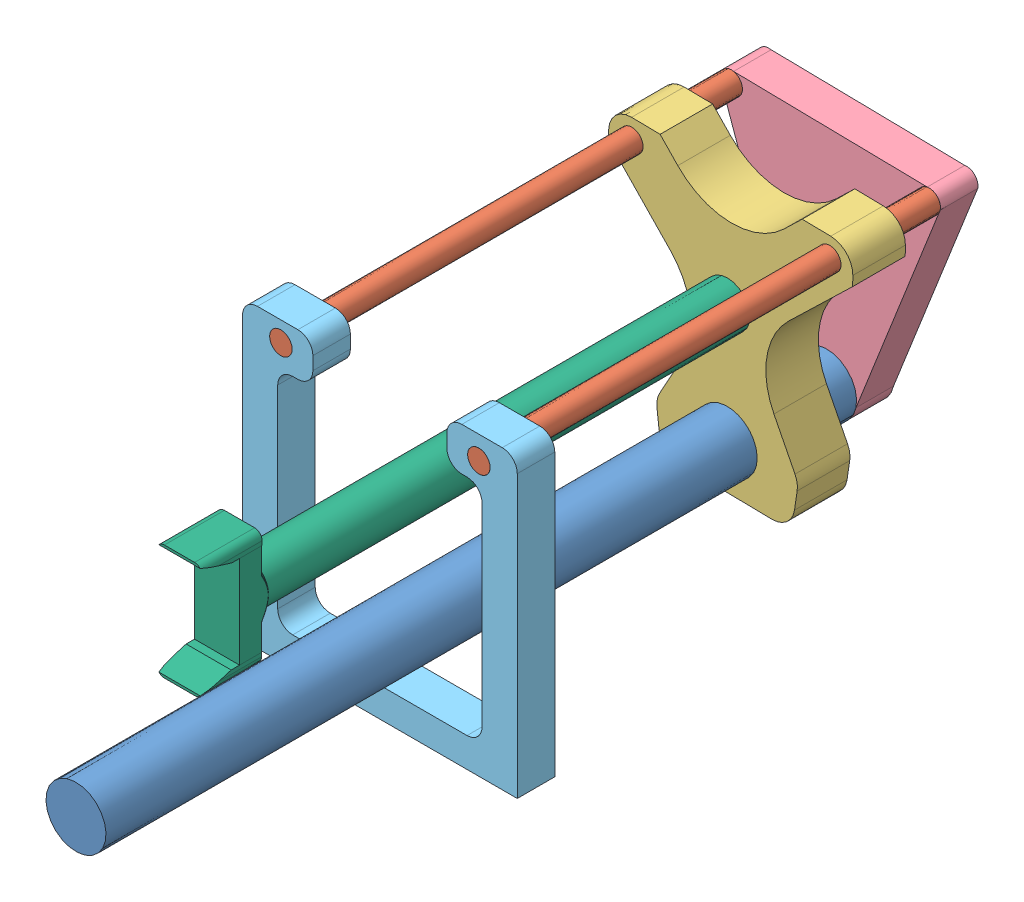
SolidWorks assembly Assem121, configuration Default. Lengths in mm.
Overall size (39.11 46.62 105).
8 component instances, 7 part files, 12 mates.
Components (placement in the parent):
- Partscrew-1: Partscrew [Default] at (36.3592 53.5498 26.3425) x (-0.97731 0.211815 0) z (0 0 1) size (8 8 100)
- Partrod-1: Partrod [Default] at (23.6562 81.9048 26.3425) size (3 3 60)
- Partrod-2: Partrod [Default] at (50.031 81.4507 86.3425) x (-0.449894 0.893082 0) z (0 0 -1) size (3 3 60)
- Partbase-1: Partbase [Default] at (36.624 68.9236 39.587) x (0 0 -1) z (0.999852 -0.017217 0) size (7 36.7 32.53)
- Part1^Assem121-1: Part1^Assem121 [Default] at (36.3592 53.5498 26.3425) x (0.97731 -0.211815 0) z (0 0 -1) size (28.87 35.66 5) (virtual)
- Part3^Assem121-1: Part3^Assem121 [Default] at origin (virtual)
- Part5^Assem121-1: Part5^Assem121 [Default] at (23.6562 81.9048 81.3425) size (36.61 46.62 5) (virtual)
- Partrod33-1: Partrod33 [Default] at (36.3928 69.376 39.587) size (9.64 17.18 73)
Mates (geometry in assembly coordinates):
- Coincident6: coincident aligned: plane of Partscrew-1 through (36.3592 53.5498 26.3425) normal (0 0 -1); plane of Partrod-2 through (50.031 81.4507 26.3425) normal (0 0 -1)
- Coincident7: coincident aligned: plane of Partscrew-1 through (36.3592 53.5498 26.3425) normal (0 0 -1); plane of Partrod-1 through (23.6562 81.9048 26.3425) normal (0 0 -1)
- Concentric2: concentric anti-aligned: circle of Partscrew-1; circle of Partbase-1
- Concentric3: concentric anti-aligned: circle of Partrod-1; circle of Partbase-1
- Concentric4: concentric aligned: circle of Partrod-2; circle of Partbase-1
- Coincident12: coincident aligned: plane of Partscrew-1 through (36.3592 53.5498 26.3425) normal (0 0 -1); plane of Partrod-2 through (50.031 81.4507 26.3425) normal (0 0 -1)
- InPlace1: in place: plane of Partscrew-1 through (36.3592 53.5498 26.3425) normal (0 0 -1); plane of ? through (0 0 26.3425) normal (0 0 -1); moOrthogonalPlaneRef_w of Partscrew-1 through (36.3592 53.5498 26.3425) normal (0 0 -1); plane of ? through (0 0 26.3425) normal (0 1 0); plane of Partscrew-1 through (36.3592 53.5498 26.3425) normal (0 0 -1); plane of ? through (0 0 26.3425) normal (-1 0 0); plane of Partscrew-1 through (36.3592 53.5498 26.3425) normal (0 0 -1); unknown of Part1^Assem121-1
- Coincident13: coincident aligned: plane of Partscrew-1; plane of Part1^Assem121-1
- Coincident14: coincident aligned: moOrthogonalPlaneRef_w of Partscrew-1 through (36.3592 53.5498 26.3425) normal (-0.211815 -0.97731 0); plane of Part1^Assem121-1 through (36.3592 53.5498 26.3425) normal (-0.211815 -0.97731 0)
- Coincident15: coincident anti-aligned: moOrthogonalPlaneRef_w of Partscrew-1 through (36.3592 53.5498 26.3425) normal (-0.97731 0.211815 0); plane of Part1^Assem121-1 through (36.3592 53.5498 26.3425) normal (0.97731 -0.211815 0)
- Coincident21: coincident aligned: plane of Partrod-1 through (23.6562 81.9048 86.3425) normal (0 0 1); plane of Part5^Assem121-1 through (53.1492 82.5459 86.3425) normal (0 0 1)
- Coincident22: coincident anti-aligned: plane of Partbase-1 through (51.507 64.2928 39.587) normal (0 0 1); plane of Partrod33-1 through (36.3928 69.376 39.587) normal (0 0 -1)
